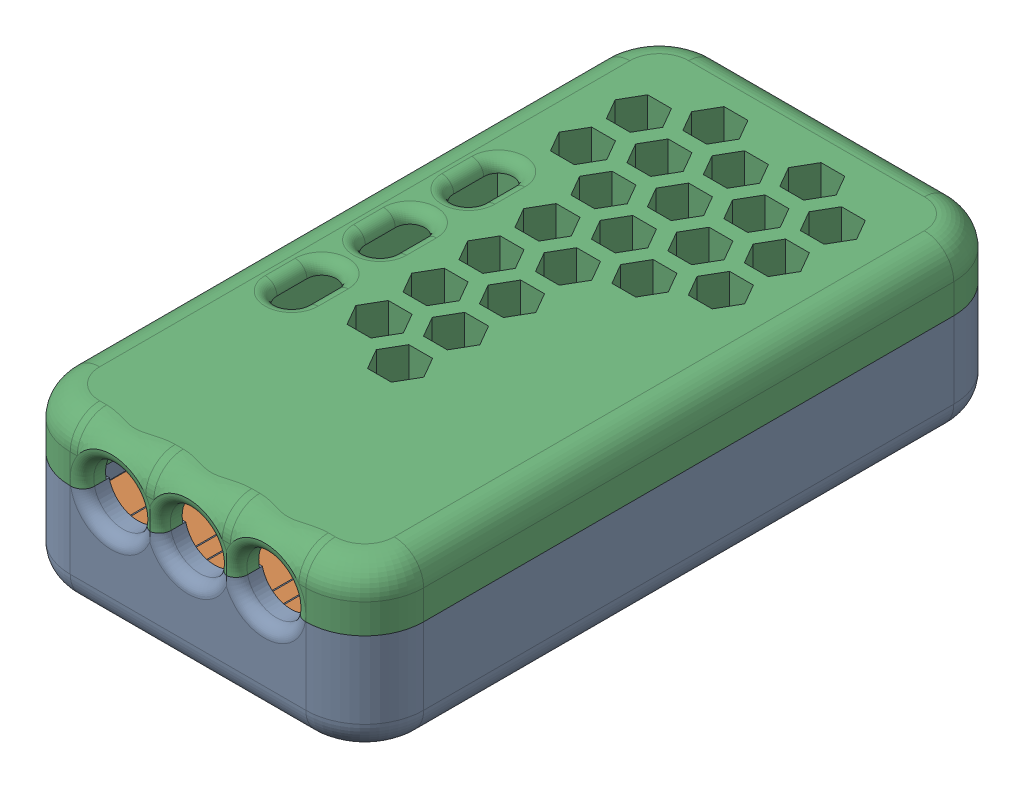
SolidWorks assembly LaBoite, configuration Défaut. Lengths in mm.
Overall size (60 28 110.12).
3 component instances, 3 part files, 6 mates.
Components (placement in the parent):
- Base-1: Base [Défaut] at origin size (60 18 110.12)
- PCB-1: PCB [Défaut] at (25 10 50.0001) x (0 0 -1) z (0 1 0) size (99.98 49.98 0.44)
- Chapo-1: Chapo [Défaut] at (0 18 0) size (60 16.35 110.12)
Mates (geometry in assembly coordinates):
- Symétrique1: symmetric aligned: plane of PCB-1 through (-20 10 -49.9874) normal (0 0 -1); plane of PCB-1 through (20 10 49.9874) normal (0 0 1)
- Symétrique2: symmetric aligned: plane of PCB-1 through (24.9873 10 -45.0001) normal (1 0 0); plane of PCB-1 through (-24.9873 10 45.0001) normal (-1 0 0)
- Coïncidente1: coincident anti-aligned: plane of Base-1 through (-20 10 -45) normal (0 1 0); plane of PCB-1 through (0 10 0) normal (0 -1 0)
- Symétrique3: symmetric aligned: plane of Chapo-1 through (-20 28 -55) normal (0 0 -1); plane of Chapo-1 through (-20 28 55) normal (0 0 1)
- Symétrique4: symmetric aligned: plane of Chapo-1 through (30 28 45) normal (1 0 0); plane of Chapo-1 through (-30 28 45) normal (-1 0 0)
- Coïncidente2: coincident anti-aligned: plane of Base-1 through (-20 18 -45) normal (0 1 0); plane of Chapo-1 through (-20 18 -45) normal (0 -1 0)
